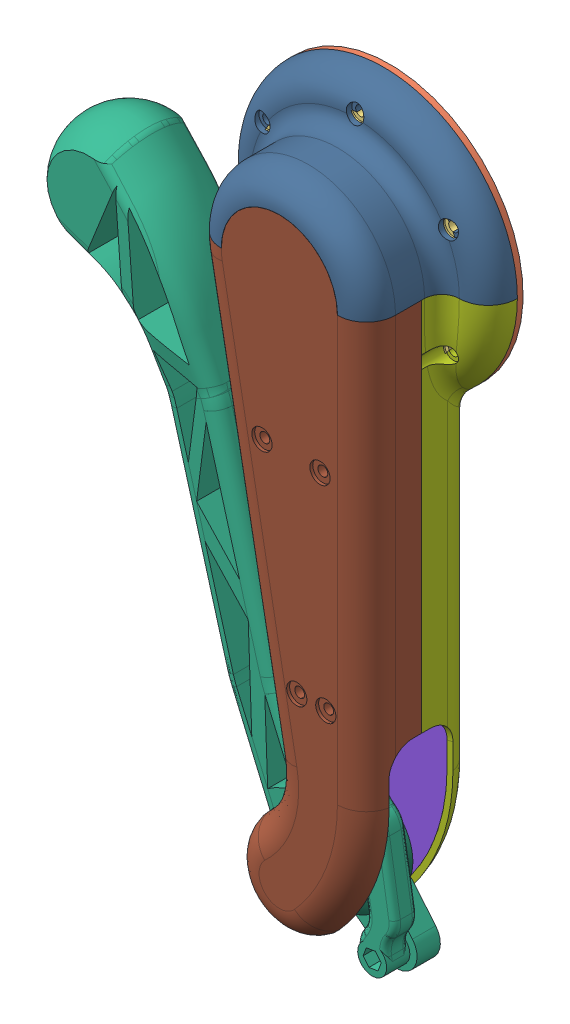
SolidWorks assembly 腿部, configuration 默认. Lengths in mm.
Overall size (160.15 273.84 40.1).
30 component instances, 24 part files, 78 mates.
Components (placement in the parent):
- 膝关节法兰轴承-1: 膝关节法兰轴承 [默认] at (-16.6752 -83.5083 230.998) x (-0.385686 -0.92263 0) z (-0.92263 0.385686 0) size (21 5 21)
- 内侧主碳板-2: 内侧主碳板 [默认] at (-16.6752 96.4917 223.998) x (0 0 1) z (-1 0 0) size (2 233 92)
- 交滚轴承座-1: 交滚轴承座 [默认] at (-16.6752 96.4917 232.498) x (-0.5 -0.866025 0) z (-0.866025 0.5 0) size (83 8.5 83)
- 曲柄输出盘-1: 曲柄输出盘 [默认] at (-16.6752 96.4917 239.498) x (-0.913999 0.405717 0) z (-0.405717 -0.913999 0) size (56 5 56)
- 连杆轴承-1: 连杆轴承 [默认] at (-26.0067 75.4697 238.498) x (-0.702251 -0.711929 0) z (0 0 1) size (10 10 4)
- 连杆-1: 连杆 [默认] at (-26.0067 75.4697 241.498) x (0.987112 0.160029 0) z (0 0 1) size (15 190 10.77)
- 外壳下盖-2: 外壳下盖 [默认] at (-16.6752 96.4917 223.998) size (92 196.8 20.76)
- 内侧碳板-2: 内侧碳板 [默认] at (13.5081 96.4917 229.998) x (0.95096 -0.309314 0) z (0 0 1) size (81.98 159.93 2.01)
- 铝件1-1: 铝件1 [默认] at (-35.2963 43.4917 228.498) x (0 0 1) z (0 1 0) size (29.16 46.62 6)
- 外壳上盖-1: 外壳上盖 [默认] at (4.2321 107.2879 151.998) size (127.43 246 36.56)
  - 外壳上盖1-1: 外壳上盖1 [默认] at (-20.9073 -10.7962 72) size (92 46 36)
  - 外壳上盖2-1: 外壳上盖2 [默认] at (-20.9073 -10.7962 72) size (60 216.8 19.56)
  - 膝关节法兰轴承-1: 膝关节法兰轴承 [默认] at (-20.9073 -190.7962 103) x (0.999154 -0.041137 0) z (0.041137 0.999154 0) size (21 5 21)
  - 编码器磁钢-1: 编码器磁钢 [默认] at (-20.9073 -190.7962 101) x (1 0 0) z (0 -1 0) size (6 3 6)
  - 磁编-1: 磁编 [默认] at (-20.9073 -190.7962 109) x (0.709654 -0.70455 0) z (0.70455 0.709654 0) size (15 2.35 16)
  - 膝关节编码器压环-1: 膝关节编码器压环 [默认] at (-20.9073 -190.7962 104) x (0.733665 0.679512 0) z (0 0 1) size (22 22 4.4)
  - 推力轴承压环-1: 推力轴承压环 [默认] at (-20.9073 -190.7962 102) x (-0.96523 -0.261403 0) z (0.261403 -0.96523 0) size (32 3 32)
  - 滚针推力轴承-1: 滚针推力轴承 [默认] at (-20.9073 -190.7962 95) x (1 0 0) z (0 -1 0) size (26 4 26)
  - 内侧碳板2-1: 内侧碳板2 [默认] at (9.276 -10.7962 102) x (0.95096 -0.309314 0) z (0 0 1) size (81.98 159.93 2.01)
- 膝关节轴-1: 膝关节轴 [默认] at (-16.6752 -83.5083 234.998) x (0.393266 -0.919425 0) z (0 0 1) size (22 12 25.09)
- 螺丝头套筒-1: 螺丝头套筒 [默认] at (-16.6752 -83.5083 229.998) x (1 0 0) z (0 1 0) size (12 4 12)
- 输出盘加强-1: 输出盘加强 [默认] at (-16.6752 96.4917 239.498) x (0.405717 0.913999 0) z (0 0 1) size (56 56 17.3)
- 连杆轴承-2: 连杆轴承 [默认] at (-26.0067 75.4697 248.498) x (0.365011 -0.931003 0) z (0 0 1) size (10 10 4)
- 滚针推力轴承-1: 滚针推力轴承 [默认] at (-16.6752 -83.5083 238.998) x (-0.966401 -0.257039 0) z (0.257039 -0.966401 0) size (26 4 26)
- 推力轴承压环-1: 推力轴承压环 [默认] at (-16.6752 -83.5083 231.998) x (0.755709 0.654908 0) z (0.654908 -0.755709 0) size (32 3 32)
- 铝件2-1: 铝件2 [默认] at (13.1619 -26.5083 228.498) x (0 0 1) z (0 1 0) size (28.91 33.6 6)
- 连杆轴承-3: 连杆轴承 [默认] at (2.7986 -102.2105 234.998) x (-0.021792 -0.999763 0) z (0 0 1) size (10 10 4)
- 电路仓-2: 电路仓 [默认] at (-3.6752 43.4917 253.998) x (0 0 -1) z (0 -1 0) size (22 15 76)
- 轴套-1: 轴套 [默认] at (2.7986 -102.2105 238.998) x (0.975892 -0.218254 0) z (0 0 -1) size (7 7 5)
- 小腿-1: 小腿 [默认] at (-16.6752 -83.5083 232.998) x (-0.919425 -0.393266 0) z (0 0 1) size (43.73 231.85 40.1)
Mates (geometry in assembly coordinates):
- 距离1: distance = 4 mm anti-aligned: plane of 膝关节法兰轴承-1 through (-16.6752 -83.5083 229.998) normal (0 0 -1); plane of 内侧主碳板-2 through (-16.6752 96.4917 225.998) normal (0 0 1)
- 同心9: concentric anti-aligned: cylinder of 膝关节法兰轴承-1 through (-16.6752 -83.5083 229.998) axis (0 0 1) radius 10.5; cylinder of 内侧主碳板-2 through (-16.6752 -83.5083 225.998) axis (0 0 -1) radius 7
- 重合19: coincident anti-aligned: plane of 膝关节法兰轴承-1 through (-16.6752 -83.5083 234.998) normal (0 0 1); plane of 滚针推力轴承-1 through (-16.6752 -83.5083 234.998) normal (0 0 -1)
- 同心10: concentric anti-aligned: cylinder of 膝关节法兰轴承-1 through (-16.6752 -83.5083 234.998) axis (0 0 -1) radius 9.5; cylinder of 滚针推力轴承-1 through (-16.6752 -83.5083 234.998) axis (0 0 1) radius 13
- 同心13: concentric aligned: cylinder of 内侧主碳板-2 through (-16.6752 96.4917 225.998) axis (0 0 -1) radius 46; cylinder of 交滚轴承座-1 through (-16.6752 96.4917 232.498) axis (0 0 -1) radius 41.5
- 重合22: coincident anti-aligned: plane of 内侧主碳板-2 through (-16.6752 96.4917 225.998) normal (0 0 1); plane of 交滚轴承座-1 through (-46.9861 113.9917 225.998) normal (0 0 -1)
- 距离3: distance = 25 mm anti-aligned: plane of 膝关节法兰轴承-2 through (-16.6752 -83.5083 250.998) normal (0 0 -1); plane of 内侧主碳板-2 through (-16.6752 96.4917 225.998) normal (0 0 1)
- 同心14: concentric anti-aligned: cylinder of 内侧主碳板-2 through (-16.6752 -83.5083 225.998) axis (0 0 -1) radius 7; circle of 膝关节法兰轴承-2
- 重合24: coincident anti-aligned: plane of 膝关节法兰轴承-2 through (-16.6752 -83.5083 250.998) normal (0 0 -1); plane of 滚针推力轴承-2 through (-16.6752 -83.5083 250.998) normal (0 0 1)
- 同心15: concentric aligned: cylinder of 膝关节法兰轴承-2 through (-16.6752 -83.5083 250.998) axis (0 0 1) radius 9.5; cylinder of 滚针推力轴承-2 through (-16.6752 -83.5083 246.998) axis (0 0 1) radius 13
- 重合28: coincident anti-aligned: circle of 内侧主碳板-2; circle of 外壳上盖-1
- 同心17: concentric aligned: cylinder of 内侧主碳板-2 through (-16.6752 59.4917 225.998) axis (0 0 -1) radius 1.7; cylinder of 交滚轴承座-1 through (-16.6752 59.4917 234.499) axis (0 0 -1) radius 1.7
- 同心18: concentric anti-aligned: cylinder of 交滚轴承座-1 through (15.3677 114.9917 234.499) axis (0 0 -1) radius 1.7; cylinder of 外壳上盖-1 through (15.3677 114.9917 230.498) axis (0 0 1) radius 1.7
- 距离4: distance = 8.5 mm anti-aligned: plane of 内侧主碳板-2 through (-16.6752 96.4917 225.998) normal (0 0 1); plane of 曲柄输出盘-1 through (-16.6752 96.4917 234.498) normal (0 0 -1)
- 同心19: concentric aligned: circle of 曲柄输出盘-1; cylinder of 内侧主碳板-2 through (-16.6752 96.4917 225.998) axis (0 0 -1) radius 46
- 重合30: coincident anti-aligned: plane of 曲柄输出盘-1 through (-16.6752 96.4917 238.498) normal (0 0 1); plane of 连杆轴承-1 through (-26.0067 75.4697 238.498) normal (0 0 -1)
- 同心24: concentric aligned: cylinder of 传动杆-1 through (-37.9969 87.8669 246.498) axis (0 0 -1) radius 5; cylinder of 连杆轴承-1 through (-26.0067 75.4697 242.498) axis (0 0 -1) radius 5
- 距离7: distance = 2 mm anti-aligned: plane of 连杆-1 through (2.7986 -102.2105 241.498) normal (0 0 -1); plane of 曲柄输出盘-1 through (-16.6752 96.4917 239.498) normal (0 0 1)
- 同心27: concentric aligned: cylinder of 连杆轴承-1 through (-26.0067 75.4697 242.498) axis (0 0 -1) radius 5; cylinder of 连杆-1 through (-26.0067 75.4697 249.498) axis (0 0 -1) radius 5
- 同心28: concentric aligned: cylinder of 小腿外型-1 through (-1.4893 -105.8329 252.998) axis (0 0 -1) radius 10; cylinder of 连杆-1 through (2.7986 -102.2105 249.498) axis (0 0 -1) radius 5
- 重合35: coincident anti-aligned: plane of 内侧主碳板-2 through (-16.6752 96.4917 225.998) normal (0 0 1); plane of 外壳下盖-2 through (-16.6752 96.4917 225.998) normal (0 0 -1)
- 同心29: concentric anti-aligned: cylinder of 内侧主碳板-2 through (-16.6752 96.4917 225.998) axis (0 0 -1) radius 46; circle of 外壳下盖-2
- 同心31: concentric anti-aligned: circle of 小腿外型-1; circle of 外壳下盖-2
- 重合40: coincident anti-aligned: circle of 内侧主碳板-2; circle of 外壳下盖-2
- 重合41: coincident aligned: cylinder of 内侧主碳板-2 through (-16.6752 96.4917 225.998) axis (0 0 -1) radius 46; circle of 外壳上盖-1/外壳上盖1-1
- 重合42: coincident anti-aligned: plane of 外壳下盖-2 through (-16.6752 96.4917 223.998) normal (0 1 0); plane of 外壳上盖-1/外壳上盖1-1 through (-16.6752 96.4917 223.998) normal (0 -1 0)
- 同心32: concentric: circle of 外壳下盖-2; cylinder of 内侧碳板-1 through (-16.6752 -83.5083 240.0649) axis (0 0 -1) radius 10
- 重合43: coincident anti-aligned: plane of 外壳下盖-2 through (-16.6752 96.4917 230.998) normal (0 0 1); plane of 内侧碳板-1 through (-16.6752 -83.5083 230.998) normal (0 0 -1)
- 同心35: concentric aligned: circle of 外壳下盖-2; circle of 内侧碳板-2
- 重合46: coincident aligned: circle of 外壳下盖-2; circle of 内侧碳板-2
- 重合50: coincident anti-aligned: plane of 外壳下盖-2 through (-16.6752 96.4917 228.498) normal (0 0 1); plane of 铝件1-1 through (-35.2963 49.4917 228.498) normal (0 0 -1)
- 重合51: coincident anti-aligned: plane of 外壳下盖-2 through (-35.2963 43.4917 230.998) normal (0 1 0); plane of 铝件1-1 through (-35.2963 43.4917 228.498) normal (0 -1 0)
- 重合52: coincident anti-aligned: plane of 外壳下盖-2 through (-35.2963 43.4917 228.498) normal (1 0 0); plane of 铝件1-1 through (-35.2963 49.4917 253.998) normal (-1 0 0)
- 重合53: coincident aligned: circle of 外壳下盖-2; circle of 外壳上盖-1/外壳上盖1-1
- 重合55: coincident anti-aligned: plane of 膝关节法兰轴承-2 through (-16.6752 -83.5083 255.998) normal (0 0 1); plane of 膝关节磁钢套筒-1 through (-16.6752 -83.5083 255.998) normal (0 0 -1)
- 同心37: concentric aligned: circle of 膝关节法兰轴承-2; circle of 膝关节磁钢套筒-1
- 重合58: coincident anti-aligned: plane of 编码器磁钢-1 through (-16.6752 -83.5083 255.998) normal (0 0 1); plane of 膝关节磁钢套筒-1 through (-16.6752 -83.5083 255.998) normal (0 0 -1)
- 同心38: concentric aligned: cylinder of 膝关节法兰轴承-2 through (-16.6752 -83.5083 255.999) axis (0 0 -1) radius 5; cylinder of 编码器磁钢-1 through (-16.6752 -83.5083 255.998) axis (0 0 -1) radius 3
- 重合60: coincident anti-aligned: plane of 膝关节轴-1 through (-15.6046 -88.3923 252.998) normal (-0.976808 -0.214117 0); plane of 膝关节磁钢套筒-1 through (-16.0329 -86.4387 250.998) normal (0.976808 0.214117 0)
- 重合61: coincident anti-aligned: plane of 膝关节轴-1 through (-16.6752 -83.5083 252.998) normal (0 0 1); plane of 膝关节磁钢套筒-1 through (-16.6752 -83.5083 252.998) normal (0 0 -1)
- 同心39: concentric aligned: cylinder of 膝关节法兰轴承-2 through (-16.6752 -83.5083 251.498) axis (0 0 -1) radius 6; cylinder of 膝关节轴-1 through (-16.6752 -83.5083 250.998) axis (0 0 -1) radius 6
- 同心40: concentric anti-aligned: cylinder of 膝关节法兰轴承-1 through (-16.6752 -83.5083 229.997) axis (0 0 1) radius 5; cylinder of 螺丝头套筒-1 through (-16.6752 -83.5083 232.998) axis (0 0 -1) radius 5
- 重合62: coincident anti-aligned: plane of 膝关节法兰轴承-1 through (-16.6752 -83.5083 229.998) normal (0 0 -1); plane of 螺丝头套筒-1 through (-16.6752 -83.5083 229.998) normal (0 0 1)
- 距离10: distance = 1 mm anti-aligned: plane of 小腿外型-1 through (-90.5325 80.6414 232.998) normal (0 0 -1); plane of 内侧碳板-2 through (13.5081 96.4917 231.998) normal (0 0 1)
- 重合63: coincident anti-aligned: plane of 膝关节法兰轴承-2 through (-16.6752 -83.5083 254.998) normal (0 0 -1); plane of 内侧碳板-3 through (13.5081 96.4917 254.998) normal (0 0 1)
- 同心41: concentric anti-aligned: cylinder of 膝关节法兰轴承-2 through (-16.6752 -83.5083 250.998) axis (0 0 1) radius 9.5; cylinder of 内侧碳板-3 through (-16.6752 -83.5083 254.998) axis (0 0 -1) radius 9.5
- 重合64: coincident aligned: plane of 铝件1-1 through (-35.2963 49.4917 253.998) normal (-1 0 0); plane of 内侧碳板-3 through (-35.2963 96.4917 254.998) normal (-1 0 0)
- 距离13: distance = 2 mm anti-aligned: plane of 编码器磁钢-1 through (-16.6752 -83.5083 255.998) normal (0 0 1); plane of 磁编-1 through (-16.6752 -83.5083 257.998) normal (0 0 -1)
- 同心42: concentric anti-aligned: cylinder of 膝关节磁钢套筒-1 through (-16.6752 -83.5083 256.998) axis (0 0 -1) radius 7; cylinder of 磁编-1 through (-16.6752 -83.5083 259.748) axis (0 0 1) radius 9
- 重合65: coincident anti-aligned: plane of 外壳下盖-2 through (-16.6752 96.4917 223.998) normal (0 1 0); plane of 外壳上盖-2/外壳上盖1-1 through (-16.6752 96.4917 223.998) normal (0 -1 0)
- 重合66: coincident anti-aligned: circle of 内侧主碳板-2; circle of 外壳上盖-2/外壳上盖1-1
- 同心43: concentric anti-aligned: circle of 连杆-1; circle of 连杆轴承-2
- 重合76: coincident anti-aligned: plane of 连杆-1 through (-26.0067 75.4697 248.498) normal (0 0 1); plane of 连杆轴承-2 through (-26.0067 75.4697 248.498) normal (0 0 -1)
- 同心44: concentric aligned: cylinder of 膝关节法兰轴承-1 through (-16.6752 -83.5083 229.997) axis (0 0 1) radius 5; cylinder of 膝关节轴-1 through (-16.6752 -83.5083 232.998) axis (0 0 1) radius 5
- 重合77: coincident anti-aligned: plane of 膝关节法兰轴承-1 through (-16.6752 -83.5083 234.998) normal (0 0 1); plane of 膝关节轴-1 through (-16.6752 -83.5083 234.998) normal (0 0 -1)
- 重合78: coincident anti-aligned: plane of 膝关节法兰轴承-1 through (-16.6752 -83.5083 234.998) normal (0 0 1); plane of 滚针推力轴承-1 through (-16.6752 -83.5083 234.998) normal (0 0 -1)
- 重合79: coincident anti-aligned: plane of 内侧碳板-2 through (13.5081 96.4917 231.998) normal (0 0 1); plane of 推力轴承压环-1 through (-16.6752 -83.5083 231.998) normal (0 0 -1)
- 同心45: concentric anti-aligned: circle of 内侧碳板-2; circle of 推力轴承压环-1
- 重合87: coincident anti-aligned: plane of 内侧碳板-2 through (2.3248 96.4917 231.998) normal (-1 0 0); plane of 铝件2-1 through (2.3248 -20.5083 231.998) normal (1 0 0)
- 重合88: coincident anti-aligned: plane of 内侧碳板-2 through (13.5081 -20.5083 231.998) normal (0 -1 0); plane of 铝件2-1 through (13.1619 -20.5083 228.498) normal (0 1 0)
- 重合89: coincident anti-aligned: plane of 内侧碳板-2 through (13.5081 96.4917 231.998) normal (0 0 1); plane of 铝件2-1 through (2.3248 -20.5083 231.998) normal (0 0 -1)
- 重合95: coincident anti-aligned: plane of 铝件1-1 through (-35.2963 43.4917 228.498) normal (0 -1 0); plane of 电路仓-1 through (-3.6752 43.4917 253.998) normal (0 1 0)
- 重合96: coincident anti-aligned: plane of 内侧碳板-2 through (13.5081 96.4917 231.998) normal (0 0 1); plane of 电路仓-1 through (11.3248 41.4917 231.998) normal (0 0 -1)
- 重合97: coincident aligned: plane of 铝件1-1 through (11.3248 49.4917 228.498) normal (1 0 0); plane of 电路仓-1 through (11.3248 41.4917 253.998) normal (1 0 0)
- 重合98: coincident anti-aligned: plane of 铝件1-1 through (-35.2963 43.4917 228.498) normal (0 -1 0); plane of 电路仓-2 through (-3.6752 43.4917 253.998) normal (0 1 0)
- 重合99: coincident anti-aligned: plane of 内侧碳板-2 through (13.5081 96.4917 231.998) normal (0 0 1); plane of 电路仓-2 through (11.3248 41.4917 231.998) normal (0 0 -1)
- 重合100: coincident aligned: plane of 铝件1-1 through (11.3248 49.4917 228.498) normal (1 0 0); plane of 电路仓-2 through (11.3248 41.4917 253.998) normal (1 0 0)
- 重合103: coincident anti-aligned: plane of 连杆-1 through (2.7986 -102.2105 238.998) normal (0 0 -1); plane of 轴套-1 through (2.7986 -102.2105 238.998) normal (0 0 1)
- 同心56: concentric anti-aligned: cylinder of 连杆轴承-3 through (2.7986 -102.2105 238.998) axis (0 0 -1) radius 2.5; cylinder of 轴套-1 through (2.7986 -102.2105 234.998) axis (0 0 1) radius 2.5
- 重合104: coincident anti-aligned: plane of 曲柄输出盘-1 through (-16.6752 96.4917 239.498) normal (0 0 1); plane of 输出盘加强-1 through (-16.6752 96.4917 239.498) normal (0 0 -1)
- 同心57: concentric anti-aligned: cylinder of 曲柄输出盘-1 through (-16.6752 96.4917 234.498) axis (0 0 1) radius 28; cylinder of 输出盘加强-1 through (-16.6752 96.4917 254.498) axis (0 0 -1) radius 28
- 同心58: concentric anti-aligned: cylinder of 曲柄输出盘-1 through (-26.0067 75.4697 238.498) axis (0 0 1) radius 5; cylinder of 连杆轴承-1 through (-26.0067 75.4697 242.498) axis (0 0 -1) radius 5
- 同心59: concentric anti-aligned: cylinder of 曲柄输出盘-1 through (-36.2133 86.9353 234.498) axis (0 0 1) radius 2.15; cylinder of 输出盘加强-1 through (-36.2133 86.9353 257.498) axis (0 0 -1) radius 2.15
- 重合105: coincident anti-aligned: plane of 膝关节轴-1 through (-13.0775 -78.7065 246.998) normal (0.599612 0.800291 0); plane of 小腿-1 through (-13.0775 -78.7065 263.0489) normal (-0.599612 -0.800291 0)
- 同心60: concentric aligned: cylinder of 膝关节轴-1 through (-16.6752 -83.5083 250.998) axis (0 0 -1) radius 6; cylinder of 小腿-1 through (-16.6752 -83.5083 263.0489) axis (0 0 -1) radius 6
- 重合106: coincident aligned: plane of 膝关节轴-1 through (-16.6752 -83.5083 246.998) normal (0 0 1); plane of 小腿-1 through (-16.6752 -83.5083 246.998) normal (0 0 1)
- 同心61: concentric aligned: cylinder of 连杆轴承-3 through (2.7986 -102.2105 238.998) axis (0 0 -1) radius 5; cylinder of 小腿-1 through (2.7986 -102.2105 238.998) axis (0 0 -1) radius 5
- 同心62: concentric aligned: cylinder of 连杆-1 through (2.7986 -102.2105 249.498) axis (0 0 -1) radius 5; cylinder of 小腿-1 through (2.7986 -102.2105 252.998) axis (0 0 -1) radius 7
